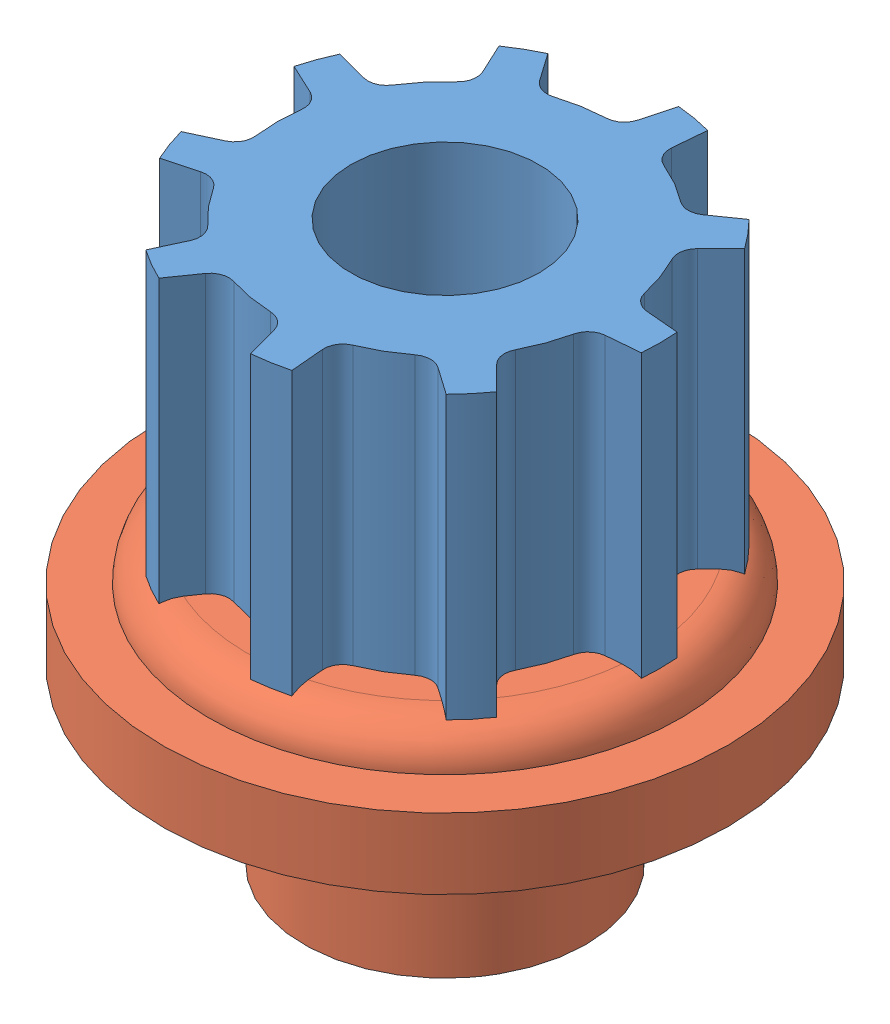
SolidWorks assembly motor assembly, configuration Default. Lengths in mm.
Overall size (16.67 11.86 16.67).
2 component instances, 2 part files, 4 mates.
Components (placement in the parent):
- motor pulley-1: motor pulley [Default] at (0 -20.1 0) x (1 0 0) z (0 -1 0) size (8.98 9.1 6.7)
- encoder wheel mount-1: encoder wheel mount [Default] at (0 -28.3 0) x (-0.562764 0 0.826618) z (-0.826618 0 -0.562764) size (12 5.96 12)
Mates (geometry in assembly coordinates):
- Concentric1: concentric aligned: cylinder of motor shaft-1 through (0 -33.4 0) axis (0 1 0) radius 1.995; cylinder of motor pulley-1 through (0 -26.8 0) axis (0 1 0) radius 2
- Concentric2: concentric anti-aligned: cylinder of motor shaft-1 through (0 -33.4 0) axis (0 1 0) radius 1.995; cylinder of encoder wheel mount-1 through (0 -24.3 0) axis (0 -1 0) radius 2
- Coincident4: coincident anti-aligned: plane of motor pulley-1 through (0 -26.8 0) normal (0 -1 0); plane of encoder wheel mount-1 through (0 -26.8 0) normal (0 1 0)
- Distance3: distance = 20.1 mm aligned: plane of motor pulley-1 through (0 -20.1 0) normal (0 1 0); plane of motor shaft-1 through (0 0 0) normal (0 1 0)
